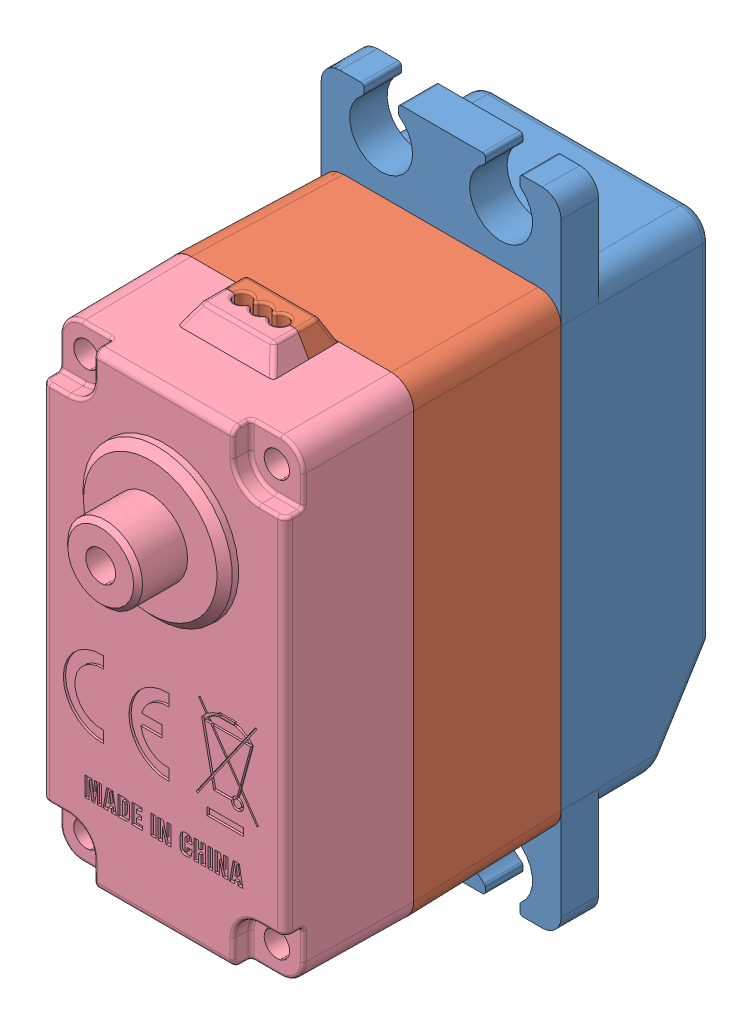
SolidWorks assembly SR311外观, configuration 默认. Lengths in mm.
Overall size (16.35 42.81 37.35).
5 component instances, 4 part files, 0 mates.
Components (placement in the parent):
- 17G-SM-S3317M_ASM_11_ASM_2_ASM-1: 17G-SM-S3317M_ASM_11_ASM_2_ASM [默认] at origin size (16.35 42.81 37.35)
  - KE-01_9_1-1: KE-01_9_1 [默认] at origin size (16 42.81 11.52)
  - KE-02_7_1-1: KE-02_7_1 [默认] at origin size (16.35 32.68 12.06)
  - 04X33-05_3_1-1: 04X33-05_3_1 [默认] at (0 7.5 -3.05) size (4.97 4.97 4.58)
  - 311-XK_8_1-1: 311-XK_8_1 [默认] at origin size (16.35 32.68 12.7)
